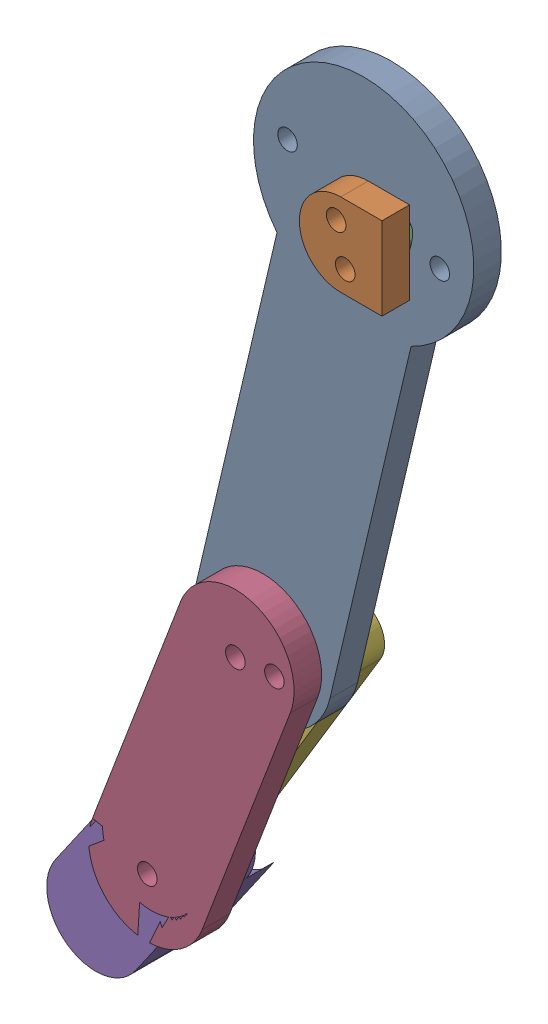
SolidWorks assembly Finger, configuration Default. Lengths in mm.
Overall size (40.03 83.73 7.5).
6 component instances, 6 part files, 15 mates.
Components (placement in the parent):
- PhalanxProximal-1: PhalanxProximal [Default] at (-15.641 13.2163 -38.0012) x (0.228538 0.973535 0) z (0 0 1) size (56.25 20 2.5)
- MetacarpalJoint-1: MetacarpalJoint [Default] at (-15.641 13.2163 -35.5012) size (7.5 7.5 2.5)
- MetacarpalLink-1: MetacarpalLink [Default] at (-14.8123 9.7644 -40.5012) x (0.354269 0.935143 0) z (0 0 1) size (41.7 3.55 2.5)
- PhalanxMiddle-2: PhalanxMiddle [Default] at (-24.7825 -25.7251 -603.5205) x (0.355469 0.934688 0) z (0 0 1) size (33.15 10.65 2.5)
- PhalanxDistal-1: PhalanxDistal [Default] at (-32.7806 -46.7556 -33.0012) x (-0.570207 -0.821501 0) z (0 0 -1) size (17.76 8.88 7.5)
- PhalangealLink-1: PhalangealLink [Default] at (-26.6342 -34.3761 -40.5012) x (0.517736 0.855541 0) z (0 0 1) size (25.83 5 2.5)
Mates (geometry in assembly coordinates):
- MetacarpalPhalangealJoint: concentric aligned: cylinder of PhalanxProximal-1 through (-15.641 13.2163 -35.5012) axis (0 0 -1) radius 0.8875; cylinder of MetacarpalJoint-1 through (-15.641 13.2163 -33.0012) axis (0 0 -1) radius 0.8875
- Coincident6: coincident anti-aligned: plane of PhalanxProximal-1 through (-24.7825 -25.7251 -35.5012) normal (0 0 1); plane of MetacarpalJoint-1 through (-15.2266 11.4904 -35.5012) normal (0 0 -1)
- Coincident9: coincident anti-aligned: plane of MetacarpalLink-1 through (-28.3276 -25.9113 -38.0012) normal (0 0 1); plane of PhalanxProximal-1 through (-24.7825 -25.7251 -38.0012) normal (0 0 -1)
- Coincident10: coincident anti-aligned: circle of MetacarpalJoint-1; cylinder of MetacarpalLink-1 through (-14.8123 9.7644 -38.0012) axis (0 0 -1) radius 0.8875
- Slot1: slot aligned: cylinder of PhalanxProximal-1 through (-25.8613 -22.3429 -35.5012) axis (0 0 -1) radius 0.8875; cylinder of MetacarpalLink-1 through (-28.3276 -25.9113 -38.0012) axis (0 0 -1) radius 0.8875; cylinder of PhalanxProximal-1 through (-28.323 -25.9845 -35.5012) axis (0 0 -1) radius 0.8875
- Slot2: slot aligned: cylinder of PhalanxProximal-1 through (-15.641 13.2163 -35.5012) axis (0 0 -1) radius 4.4375; cylinder of MetacarpalLink-1 through (-14.8123 9.7644 -38.0012) axis (0 0 -1) radius 0.8875; cylinder of PhalanxProximal-1 through (-12.091 13.2342 -35.5012) axis (0 0 -1) radius 0.8875
- Concentric20: concentric aligned: cylinder of PhalanxProximal-1 through (-24.7825 -25.7251 -35.5012) axis (0 0 -1) radius 0.8875; cylinder of PhalanxMiddle-2 through (-24.7825 -25.7251 -33.0012) axis (0 0 -1) radius 0.8875
- Coincident19: coincident anti-aligned: plane of PhalanxProximal-1 through (-24.7825 -25.7251 -35.5012) normal (0 0 1); plane of PhalanxMiddle-2 through (-32.7806 -46.7556 -35.5012) normal (0 0 -1)
- Parallel6: parallel aligned: plane of PhalanxProximal-1 through (-55.641 19.4663 -35.5012) normal (0 1 0); plane of MetacarpalJoint-1 through (-15.2266 15.2404 -33.0012) normal (0 1 0)
- Parallel8: parallel aligned: plane of PhalanxProximal-1; plane of PhalanxMiddle-2
- Concentric22: concentric anti-aligned: cylinder of PhalanxMiddle-2 through (-32.7806 -46.7556 -33.0012) axis (0 0 -1) radius 0.8875; cylinder of PhalanxDistal-1 through (-32.7806 -46.7556 -40.5012) axis (0 0 1) radius 0.8875
- Concentric23: concentric aligned: cylinder of PhalanxProximal-1 through (-21.242 -25.4657 -35.5012) axis (0 0 -1) radius 0.8875; cylinder of PhalangealLink-1 through (-21.242 -25.4657 -38.0012) axis (0 0 -1) radius 0.8875
- Coincident22: coincident anti-aligned: plane of PhalanxProximal-1 through (-24.7825 -25.7251 -38.0012) normal (0 0 -1); plane of PhalangealLink-1 through (-32.0265 -43.2866 -38.0012) normal (0 0 1)
- Concentric25: concentric anti-aligned: cylinder of PhalanxDistal-1 through (-32.0265 -43.2866 -40.5012) axis (0 0 1) radius 0.8875; cylinder of PhalangealLink-1 through (-32.0265 -43.2866 -38.0012) axis (0 0 -1) radius 0.8875
- Coincident24: coincident aligned: plane of PhalanxMiddle-2 through (-32.7806 -46.7556 -33.0012) normal (0 0 1); plane of PhalanxDistal-1 through (-32.4035 -45.0211 -33.0012) normal (0 0 1)
